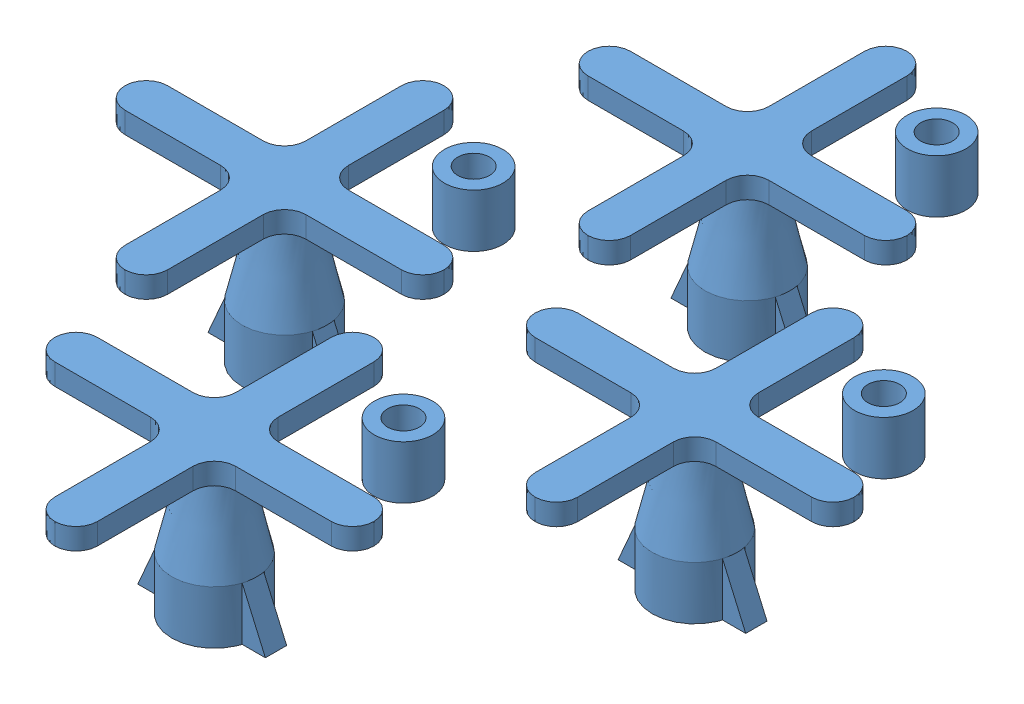
SolidWorks assembly 装配体1, configuration 默认. Lengths in mm.
Overall size (67.86 15.07 78.32).
4 component instances, 1 part files, 0 mates.
Components (placement in the parent):
- bottom_foot__tip_v1-1: bottom_foot__tip_v1 [默认] at (-11.485 -4.4454 30) size (30 15 30)
- bottom_foot__tip_v1-2: bottom_foot__tip_v1 [默认] at (-30.3395 -4.4756 6.179) size (30 15 30)
- bottom_foot__tip_v1-3: bottom_foot__tip_v1 [默认] at (-49.3405 -4.5072 30.7109) size (30 15 30)
- bottom_foot__tip_v1-4: bottom_foot__tip_v1 [默认] at (-32.1482 -4.5109 54.5028) size (30 15 30)
